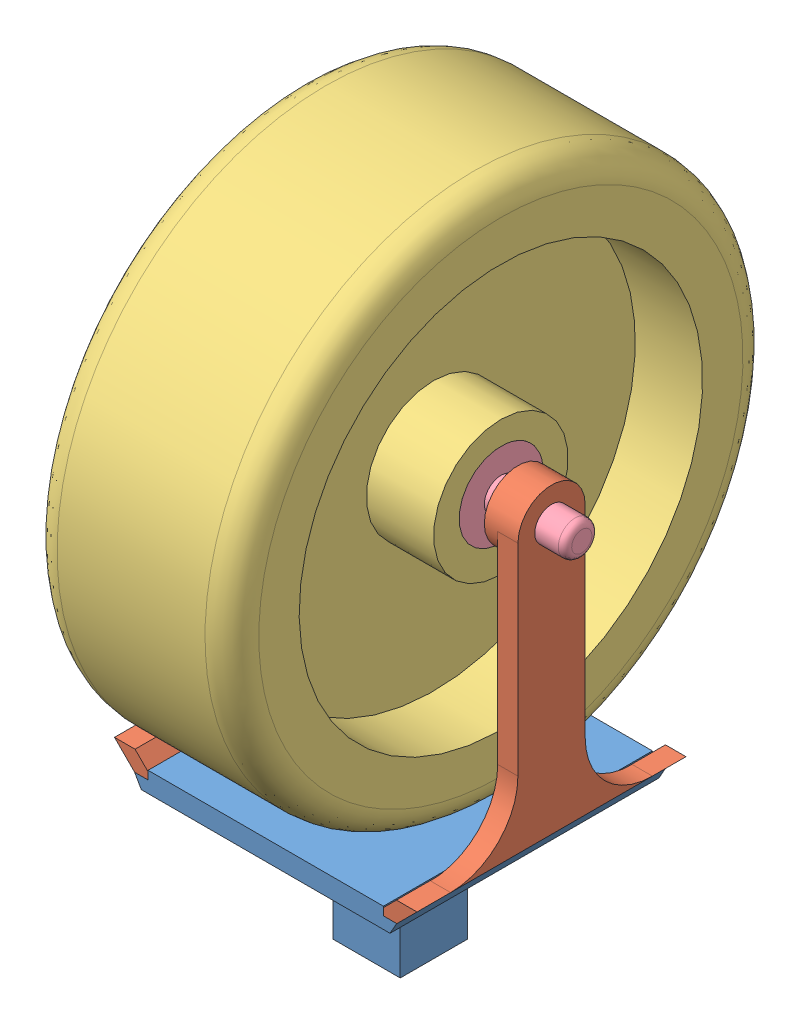
SolidWorks assembly Backwheel, configuration Default. Lengths in mm.
Overall size (137.16 277.12 226.77).
5 component instances, 4 part files, 7 mates.
Components (placement in the parent):
- Base-1: Base [Default] at (96.8885 104.0294 146.2377) size (98.97 58.42 101.6)
- Back Wheel Support-1: Back Wheel Support [Default] at (166.7385 108.4744 146.2377) x (0 0 -1) z (1 0 0) size (101.6 121.92 12.7)
- Wheel-1: Wheel [Default] at (96.8885 217.6944 146.2377) x (1 0 0) z (0 0.123644 0.992327) size (76.2 203.2 203.2)
- Back Wheel Support-2: Back Wheel Support [Default] at (27.0385 108.4744 146.2377) x (0 0 1) z (-1 0 0) size (101.6 121.92 12.7)
- Shaft-2: Shaft [Default] at (96.8885 217.6944 146.2377) x (1 0 0) z (0 -0.212383 0.977187) size (137.16 31.75 31.75)
Mates (geometry in assembly coordinates):
- Coincident1: coincident anti-aligned: plane of Base-1 through (96.8885 108.4744 146.2377) normal (0 1 0); plane of Back Wheel Support-2 through (27.0385 108.4744 171.6377) normal (0 -1 0)
- Coincident4: coincident anti-aligned: plane of Base-1 through (96.8885 108.4744 146.2377) normal (0 1 0); plane of Back Wheel Support-1 through (166.7385 108.4744 120.8377) normal (0 -1 0)
- Concentric9: concentric aligned: cylinder of Back Wheel Support-1 through (154.0385 217.6944 146.2377) axis (-1 0 0) radius 6.35; cylinder of Shaft-2 through (28.3085 217.6944 146.2377) axis (-1 0 0) radius 6.35
- Concentric10: concentric anti-aligned: cylinder of Back Wheel Support-2 through (39.7385 217.6944 146.2377) axis (1 0 0) radius 6.35; cylinder of Shaft-2 through (28.3085 217.6944 146.2377) axis (-1 0 0) radius 6.35
- Width1: width anti-aligned: plane of Back Wheel Support-2 through (39.7385 108.4744 146.2377) normal (-1 0 0); plane of Shaft-2 through (154.0385 108.4744 146.2377) normal (1 0 0); plane of Back Wheel Support-1 through (165.4685 217.6944 146.2377) normal (1 0 0); plane of Shaft-2 through (28.3085 223.8996 147.5864) normal (-1 0 0)
- Concentric11: concentric anti-aligned: cylinder of Wheel-1 through (58.7885 217.6944 146.2377) axis (1 0 0) radius 15.875; cylinder of Shaft-2 through (28.3085 217.6944 146.2377) axis (-1 0 0) radius 15.875
- Width2: width anti-aligned: plane of Back Wheel Support-2 through (39.7385 108.4744 146.2377) normal (-1 0 0); plane of Wheel-1 through (154.0385 108.4744 146.2377) normal (1 0 0); plane of Back Wheel Support-1 through (134.9885 292.5858 136.9063) normal (1 0 0); plane of Wheel-1 through (58.7885 292.5858 136.9063) normal (-1 0 0)
